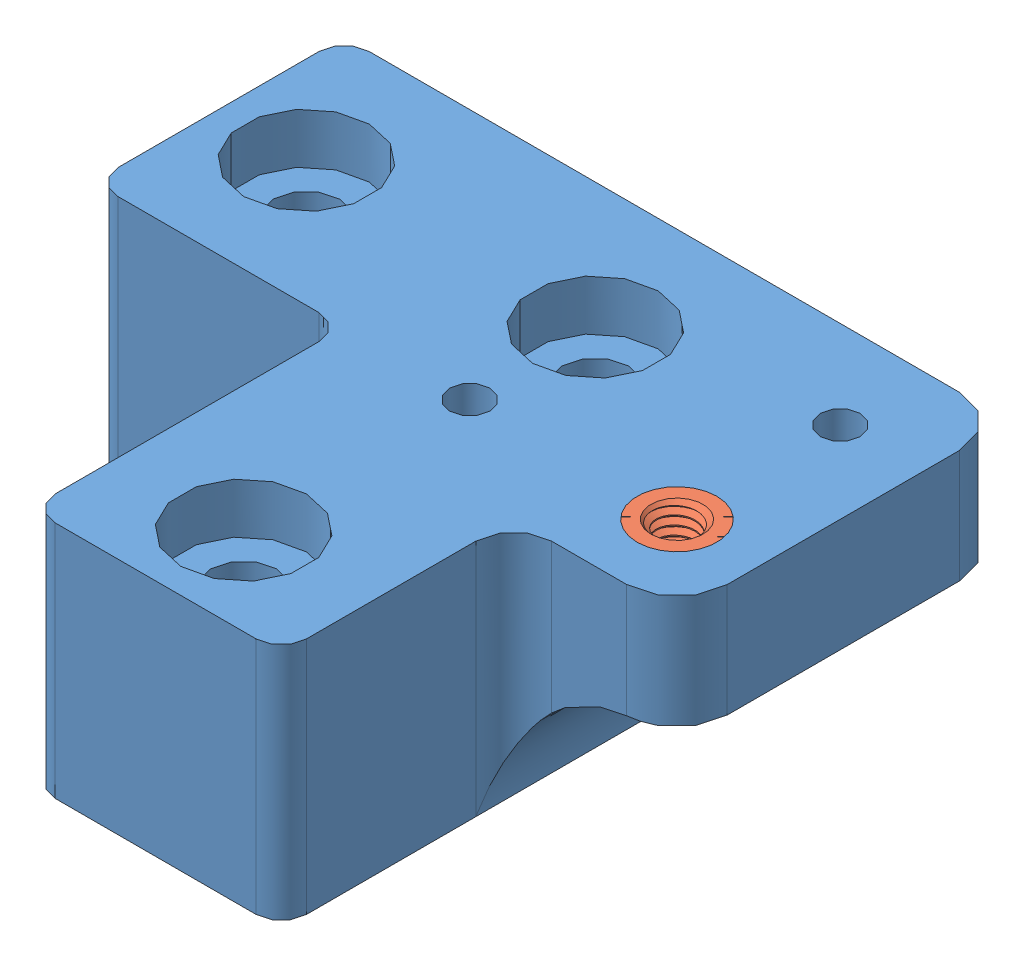
SolidWorks assembly right_corner_plate_with_insert, configuration Default. Lengths in mm.
Overall size (53 20.05 45).
2 component instances, 2 part files, 2 mates.
Components (placement in the parent):
- double_pulley_corner_bracket-1: double_pulley_corner_bracket [Right Corner Pulley Plate] at (264.071 374.0105 528.3157) size (53 19.81 45)
- m4_heat_set_insert_long_94180A353-1: m4_heat_set_insert_long_94180A353 [94180A353] at (350.571 393.0105 503.3157) size (6.35 8.38 6.35)
Mates (geometry in assembly coordinates):
- Coincident1594070888: coincident aligned: plane of double_pulley_corner_bracket-1 through (344.071 393.0105 528.3157) normal (0 1 0); plane of m4_heat_set_insert_long_94180A353-1 through (350.571 393.0105 503.3157) normal (0 1 0)
- Concentric754010292: concentric anti-aligned: cylinder of double_pulley_corner_bracket-1 through (350.571 393.0105 503.3157) axis (0 -1 0) radius 2.7; circle of m4_heat_set_insert_long_94180A353-1
